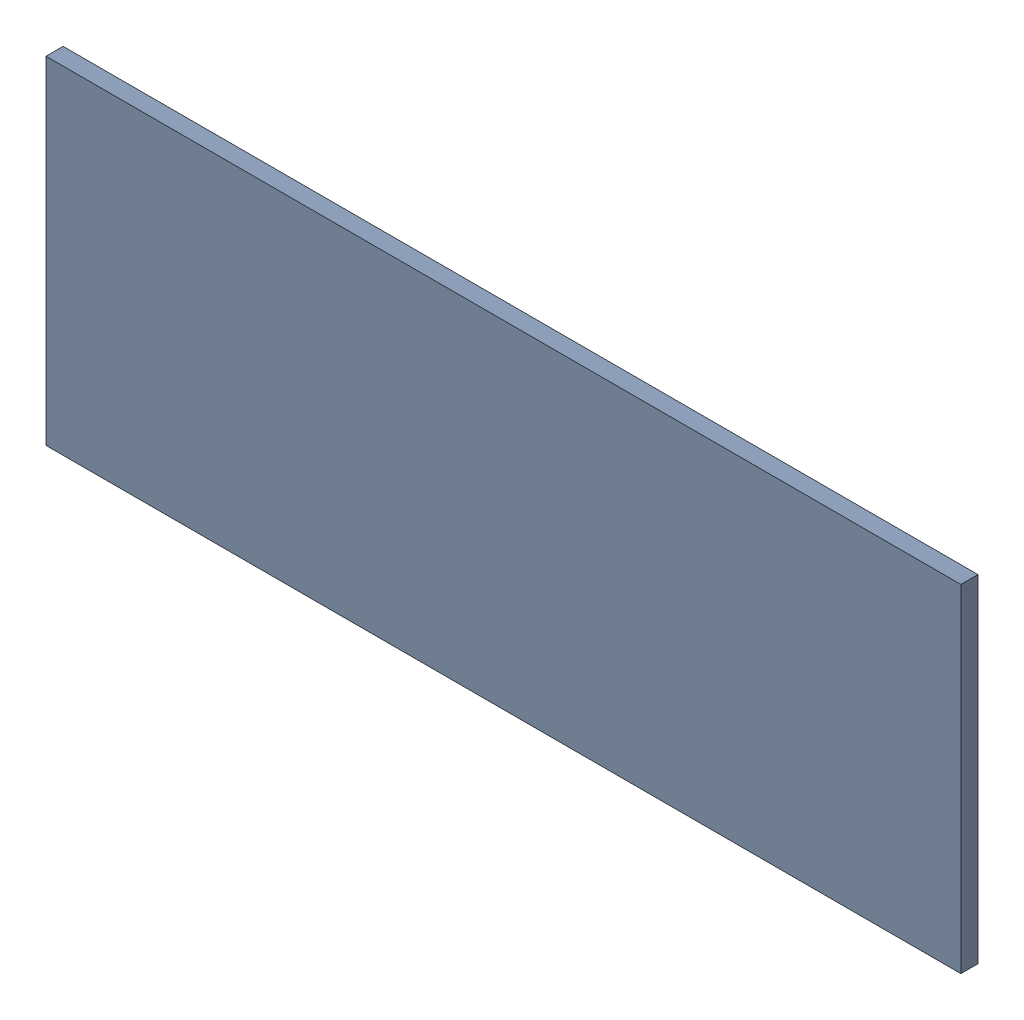
SolidWorks assembly Pad RAK4600-28(29.2mm,20mm) on Top Layer, configuration Predeterminado. Lengths in mm.
Overall size (1.9 0.7 0.04).
2 component instances, 1 part files, 0 mates.
Components (placement in the parent):
- Pad RAK4600-28(29.2mm,20mm) on Top Layer-1-1: Pad RAK4600-28(29.2mm,20mm) on Top Layer-1 [Predeterminado] at (-68.317 -44.187 -0.0457) size (1.9 0.7 0.04)
  - Pad RAK4600-28(29.2mm,20mm) on Top Layer-Part-1-1: Pad RAK4600-28(29.2mm,20mm) on Top Layer-Part-1 [Predeterminado] at origin size (1.9 0.7 0.04)
